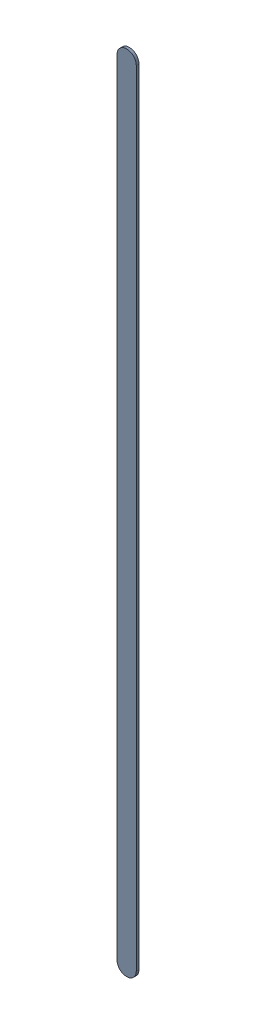
SolidWorks assembly Track (13.178mm,24.472mm)(13.178mm,34.822mm) on Top Layer, configuration Predeterminado. Lengths in mm.
Overall size (0.25 10.6 0.04).
2 component instances, 1 part files, 0 mates.
Components (placement in the parent):
- Track (13.178mm,24.472mm)(13.178mm,34.822mm) on Top Layer-1-1: Track (13.178mm,24.472mm)(13.178mm,34.822mm) on Top Layer-1 [Predeterminado] at (-68.317 -44.187 -0.0457) size (0.25 10.6 0.04)
  - Track (13.178mm,24.472mm)(13.178mm,34.822mm) on Top Layer-Part-1-1: Track (13.178mm,24.472mm)(13.178mm,34.822mm) on Top Layer-Part-1 [Predeterminado] at origin size (0.25 10.6 0.04)
